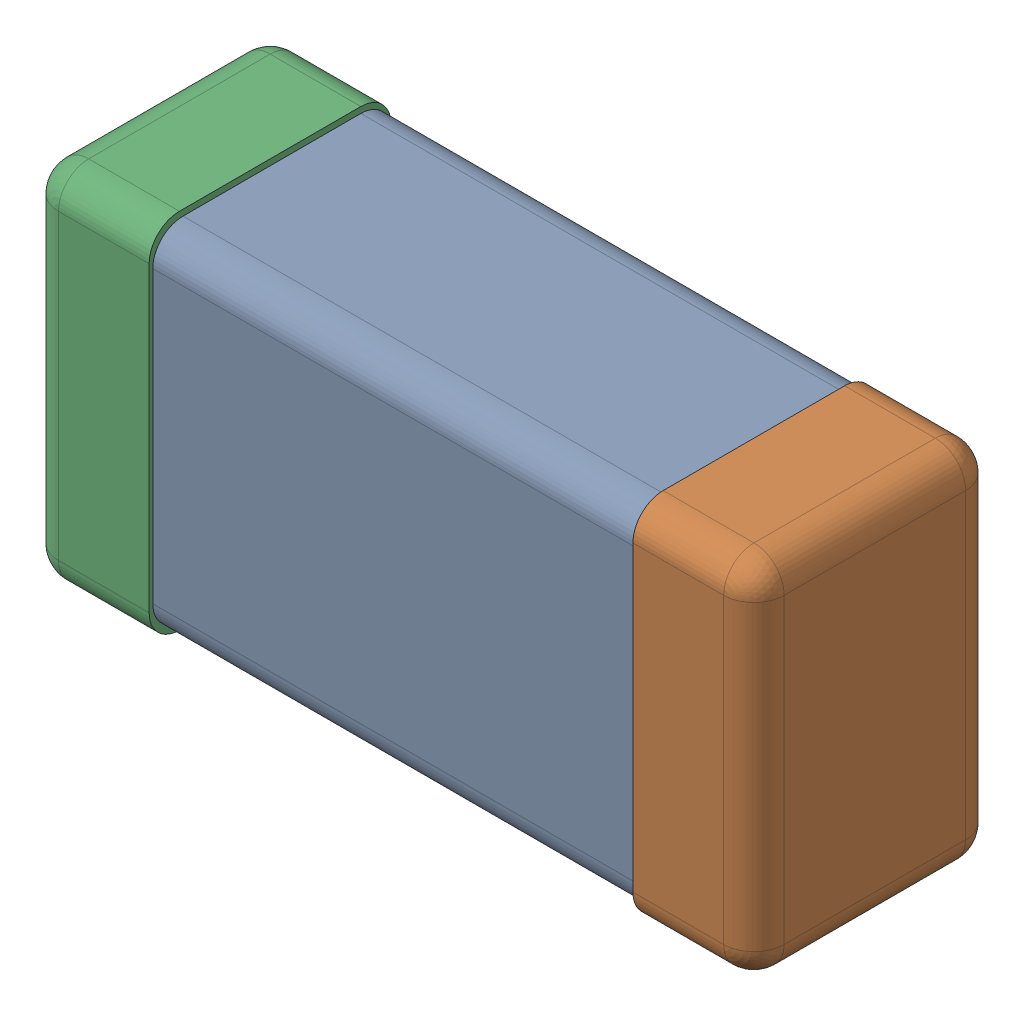
SolidWorks assembly C0201_020_8, configuration Standard. Lengths in mm.
Overall size (0.6 0.3 0.2).
4 component instances, 3 part files, 0 mates.
Components (placement in the parent):
- C0201_020_9-1: C0201_020_9 [Standard] at origin size (0.6 0.3 0.2)
  - Part 3_2-1: Part 3_2 [Standard] at (0 0 -7.3015) size (0.5 0.29 0.2)
  - Part 2_2-1: Part 2_2 [Standard] at (0 0 -7.3) size (0.1 0.3 0.2)
  - Part 1_2-1: Part 1_2 [Standard] at (0 0 -7.3) size (0.1 0.3 0.2)
